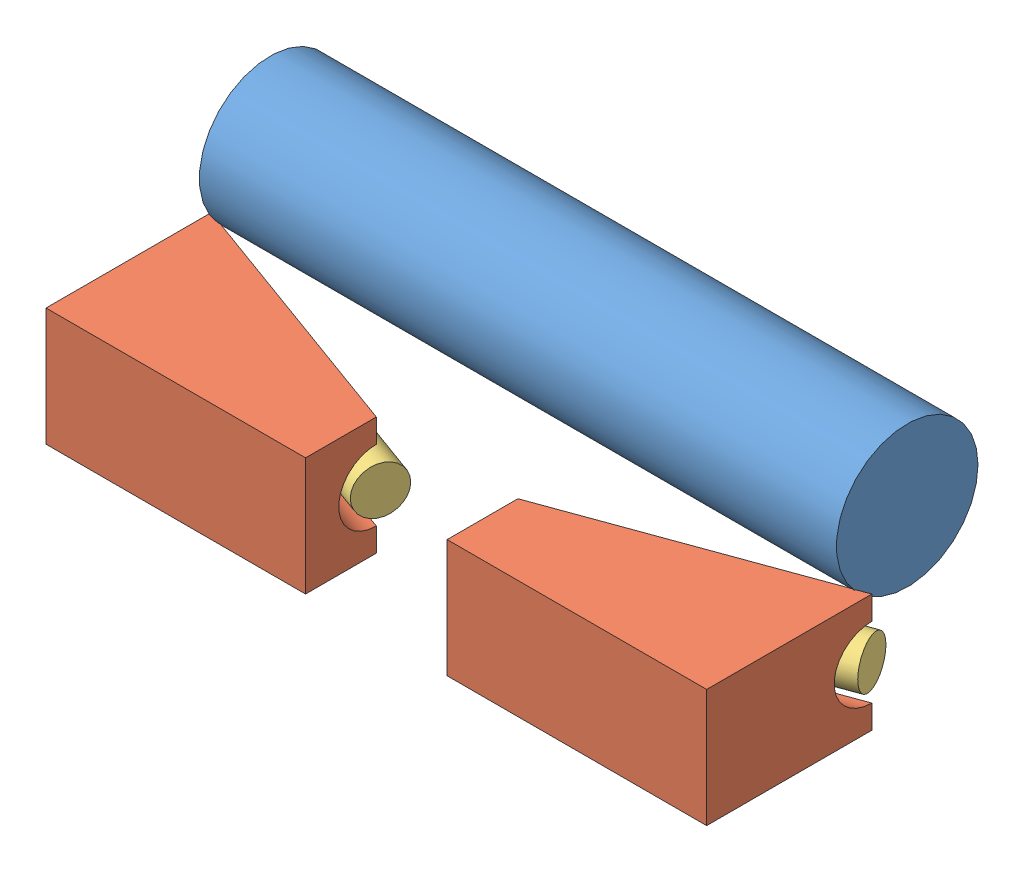
SolidWorks assembly Collection Rough Assembly, configuration Default. Lengths in mm.
Overall size (286.83 100 120).
5 component instances, 3 part files, 16 mates.
Components (placement in the parent):
- Brush - rough-1: Brush - rough [Default] at (275 70 -90) x (0 0 1) z (-1 0 0) size (60 60 270)
- Ball Guides - rough-1: Ball Guides - rough [Default] at (0 0 -30) size (110 50 70)
- Ball Guide Roller - rough-1: Ball Guide Roller - rough [Default] at (0 25 -70) x (0.341743 0 -0.939793) z (0.939793 0 0.341743) size (20 20 120)
- Ball Guides - rough-2: Ball Guides - rough [Default] at (280 50 -30) x (-1 0 0) z (0 0 1) size (110 50 70)
- Ball Guide Roller - rough-2: Ball Guide Roller - rough [Default] at (280 25 -70) x (-0.341743 0 -0.939793) z (-0.939793 0 0.341743) size (20 20 120)
Mates (geometry in assembly coordinates):
- Concentric1: concentric aligned: cylinder of Ball Guides - rough-1 through (119.635 25 -26.4964) axis (-0.939793 0 -0.341743) radius 15; cylinder of Ball Guide Roller - rough-1 through (112.7752 25 -28.9908) axis (-0.939793 0 -0.341743) radius 10
- Coincident15: coincident: point of Ball Guides - rough-1; plane of Ball Guide Roller - rough-1 through (0 25 -70) normal (-0.939793 0 -0.341743)
- Parallel1: parallel aligned: plane of Ball Guides - rough-1 through (0 0 -30) normal (0 1 0); plane of Ball Guide Roller - rough-1
- Concentric3: concentric aligned: cylinder of Ball Guides - rough-2 through (160.365 25 -26.4964) axis (0.939793 0 -0.341743) radius 15; cylinder of Ball Guide Roller - rough-2 through (167.2248 25 -28.9908) axis (0.939793 0 -0.341743) radius 10
- Coincident17: coincident: point of Ball Guides - rough-2; plane of Ball Guide Roller - rough-2 through (280 25 -70) normal (0.939793 0 -0.341743)
- Parallel2: parallel aligned: plane of Ball Guides - rough-2; plane of Ball Guide Roller - rough-2
- Coincident19: coincident aligned: plane of Ball Guides - rough-1 through (0 50 0) normal (0 0 1); plane of Ball Guides - rough-2 through (280 0 0) normal (0 0 1)
- Distance1: distance = 60 mm anti-aligned: plane of Ball Guides - rough-1 through (110 50 0) normal (1 0 0); plane of Ball Guides - rough-2 through (170 0 0) normal (-1 0 0)
- Coincident21: coincident aligned: plane of Ball Guides - rough-1 through (0 0 -30) normal (0 1 0); plane of assembly through (0 0 0) normal (0 1 0)
- Coincident23: coincident aligned: plane of Ball Guides - rough-1 through (0 50 -30) normal (0 1 0); plane of Ball Guides - rough-2 through (280 50 -30) normal (0 1 0)
- Coincident24: coincident anti-aligned: plane of Ball Guides - rough-1 through (0 50 -30) normal (-1 0 0); plane of assembly through (0 0 0) normal (1 0 0)
- Coincident25: coincident: plane of Brush - rough-1 through (140 81.0455 -90) normal (-1 0 0); plane of assembly through (140 0 0) normal (1 0 0)
- Parallel4: parallel: plane of Brush - rough-1; plane of assembly through (0 0 0) normal (0 1 0)
- Coincident27: coincident aligned: plane of Ball Guides - rough-1 through (0 50 0) normal (0 0 1); plane of assembly through (0 0 0) normal (0 0 1)
- Distance5: distance = 90 mm: line of Brush - rough-1 through (5 70 -90) axis (1 0 0); plane of assembly
- Distance6: distance = 70 mm: line of Brush - rough-1 through (5 70 -90) axis (1 0 0); plane of assembly
